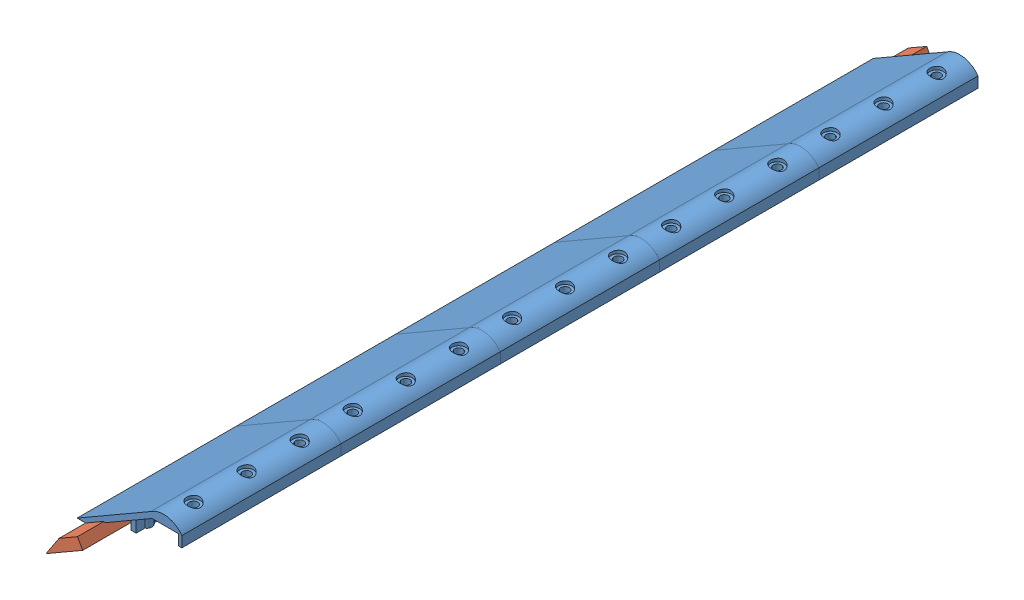
SolidWorks assembly Ensamblaje6, configuration Predeterminado. Lengths in mm.
Overall size (107.94 62.54 800).
7 component instances, 2 part files, 1 mates.
Components (placement in the parent):
- PALAS UNIDAS-1: PALAS UNIDAS [Predeterminado] at (-263.4935 73.8798 352.5759) size (98.62 43.88 750)
  - pala2-2: pala2 [Predeterminado] at (-21.0812 39.4806 175.798) size (98.62 43.88 150)
  - pala2-4: pala2 [Predeterminado] at (-21.0812 39.4806 325.798) size (98.62 43.88 150)
  - pala2-5: pala2 [Predeterminado] at (-21.0812 39.4806 475.798) size (98.62 43.88 150)
  - pala2-6: pala2 [Predeterminado] at (-21.0812 39.4806 625.798) size (98.62 43.88 150)
  - pala2-7: pala2 [Predeterminado] at (-21.0812 39.4806 25.798) size (98.62 43.88 150)
- cinta flexy Recogedor-1: cinta flexy Recogedor [Predeterminado] at (-342.1965 69.7001 678.3739) x (0 0 1) z (-0.5 0.866025 0) size (800 40 10)
Mates (geometry in assembly coordinates):
- Paralelo3: parallel: plane of PALAS UNIDAS-1/pala2-6 through (-284.5747 113.3604 1053.3739) normal (0.5 -0.866025 0); plane of cinta flexy Recogedor-1 through (-347.1965 78.3604 678.3739) normal (-0.5 0.866025 0)
